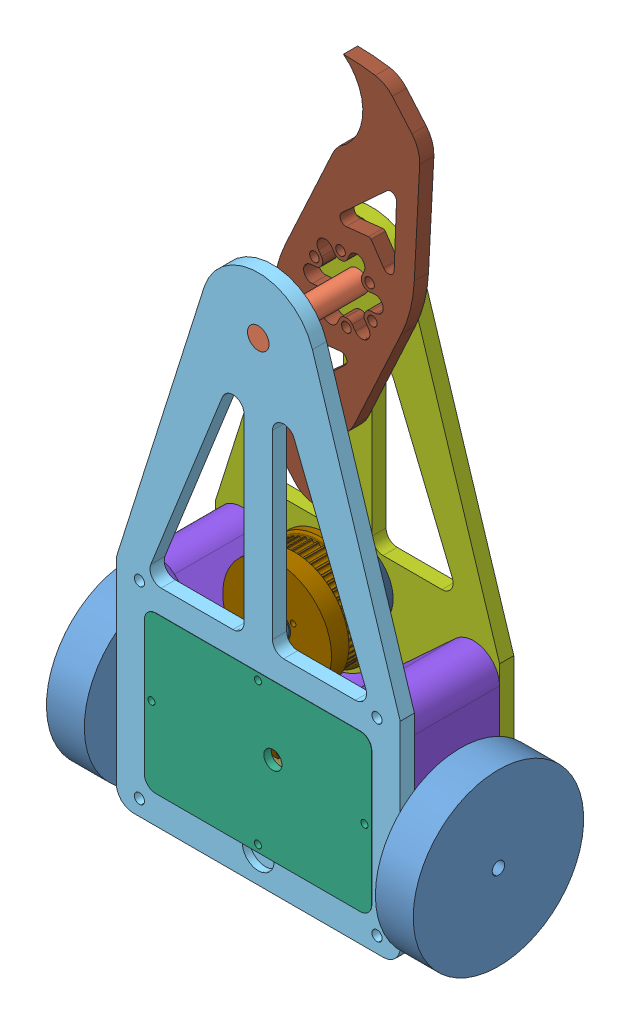
SolidWorks assembly origanal combat bot TPU, configuration Default. Lengths in mm.
Overall size (241.3 346.7 98.18).
30 component instances, 18 part files, 53 mates.
Components (placement in the parent):
- wheel-1: wheel [Default] at (-128.5875 34.925 25.4) x (-1 0 0) z (0 -0.935756 -0.352647)
- wheel-2: wheel [Default] at (1.5875 34.925 25.4) x (1 0 0) z (0 -0.978759 -0.205012)
- pin-1: pin [Default] at (-62.5126 210.1871 0) x (-0.607765 0.794117 0) z (0.794117 0.607765 0)
- 2030 4500kv with gearbox v2-1: 2030 4500kv with gearbox v2 [Default] at (-8.3063 27.0331 25.5745) x (0 -0.022102 -0.999756) z (0 -0.999756 0.022102)
- 22mm Motor Mount V1 v1-1: 22mm Motor Mount V1 v1 [Default] at (1.5875 34.925 25.4) x (0 -0.999756 0.022102) z (-1 0 0)
- 22mm Motor Mount V1 v1-2: 22mm Motor Mount V1 v1 [Default] at (-128.5875 34.925 25.4) x (0 0.999756 -0.022102) z (1 0 0)
- 2030 4500kv with gearbox v2-2: 2030 4500kv with gearbox v2 [Default] at (-118.6937 42.8169 25.2255) x (0 -0.022102 -0.999756) z (0 0.999756 -0.022102)
- Top plate-1: Top plate [Default] at (-63.5 47.625 44.45) x (0 -1 0) z (-1 0 0)
- Top cover-1: Top cover [Default] at (-63.5 47.625 47.625) x (-1 0 0) z (0 1 0)
- Bottom Plate-6: Bottom Plate [Default] at (-63.5 47.625 0) x (0 -1 0) z (-1 0 0)
- TPU Body-1: TPU Body [Default] at (-136.525 66.675 6.35) x (0 -1 0) z (-1 0 0)
- 48tooth pully_3530 motor combo-1: 48tooth pully_3530 motor combo [Default] at (-63.5 96.5708 5.35) x (0 0 1) z (0 1 0) size (36 48.63 48.63)
  - 48tooth pully_3530 motor combo.step-1: 48tooth pully_3530 motor combo.step [Default] at origin size (36 48.63 48.63)
    - 3mm 48tooth GT2 Printable v2.step-1: 3mm 48tooth GT2 Printable v2.step [Default] at (23.364 0 0) x (0 1 0) z (0 0 1) size (48.63 22.27 48.63)
    - Motor_3536.step-1: Motor_3536.step [Default] at origin size (36 35 35)
- bar weapon.STEP-1: bar weapon.STEP [Default] at (-63.5 211.8868 9.525) x (0.907959 -0.419058 0) z (0 0 1)
- 91115A203_Female Threaded Hex Standoff-1: 91115A203_Female Threaded Hex Standoff [91115A203] at (-116.6254 91.4023 25.4) x (0.5 0.866025 0) z (0 0 -1)
- 91115A203_Female Threaded Hex Standoff-2: 91115A203_Female Threaded Hex Standoff [91115A203] at (-10.3746 91.4023 25.4) x (0.5 0.866025 0) z (0 0 -1)
- 91115A203_Female Threaded Hex Standoff-3: 91115A203_Female Threaded Hex Standoff [91115A203] at (-116.6254 7.0227 25.4) x (-0.5 -0.866025 0) z (0 0 -1)
- 91115A203_Female Threaded Hex Standoff-4: 91115A203_Female Threaded Hex Standoff [91115A203] at (-10.3746 7.0227 25.4) x (-1 0 0) z (0 0 -1)
- just cuz_SwitchBoard-1: just cuz_SwitchBoard [Default] at (-56.8286 51.9533 41.05) size (48 14 17.55)
  - just cuz_SwitchBoard.stp-1: just cuz_SwitchBoard.stp [Default] at origin size (48 14 17.55)
    - XT30_Female.stp-1: XT30_Female.stp [Default] at (-4.7913 -1.9356 -6.5462) x (-1 0 0) z (0 0 -1) size (5.25 10.45 15.6)
    - XT30_Male.stp-1: XT30_Male.stp [Default] at (4.8749 -1.9112 -14.0462) size (5.25 10.45 15.5)
    - 8-32 PEM Nut Insert.stp-1: 8-32 PEM Nut Insert.stp [Default] at (0 0 -4.0856) x (1 0 0) z (0 -1 0) size (8.64 3.94 8.64)
    - XT30_Female.stp-2: XT30_Female.stp [Default] at (-10.7913 -1.9356 -6.5462) x (-1 0 0) z (0 0 -1) size (5.25 10.45 15.6)
    - XT30_Female.stp-3: XT30_Female.stp [Default] at (-16.7913 -1.9356 -6.5462) x (-1 0 0) z (0 0 -1) size (5.25 10.45 15.6)
    - 8-32 3-16 NO THREADS_ Button Head Hex Drive Screw.stp-1: 8-32 3-16 NO THREADS_ Button Head Hex Drive Screw.stp [Default] at (0 0 -0.7667) x (-1 0 0) z (0 0 1) size (7.92 7.92 6.97)
    - Switch PD Board V1.3 Bottom Connectors.stp-1: Switch PD Board V1.3 Bottom Connectors.stp [Default] at origin size (48 14 1.56)
    - Switch PD Board V1.3 Bottom Connectors-0.stp-1: Switch PD Board V1.3 Bottom Connectors-0.stp [Default] at origin size (41 14 3.4)
Mates (geometry in assembly coordinates):
- Concentric19: concentric anti-aligned: cylinder of wheel-1 through (-128.5875 34.925 25.4) axis (-1 0 0) radius 2.794; cylinder of 2030 4500kv with gearbox v2-1 through (-0.4125 34.925 25.4) axis (1 0 0) radius 3
- Parallel5: parallel anti-aligned: cylinder of wheel-2 through (1.5875 34.925 25.4) axis (1 0 0) radius 2.794; cylinder of 2030 4500kv with gearbox v2-2 through (-126.5875 34.925 25.4) axis (-1 0 0) radius 3
- Parallel14: parallel anti-aligned: plane of 2030 4500kv with gearbox v2-1 through (-0.4125 31.1877 19.4812) normal (0 -0.022102 -0.999756); plane of 22mm Motor Mount V1 v1-1 through (1.5875 31.1539 19.3684) normal (0 0.022102 0.999756)
- Concentric39: concentric anti-aligned: cylinder of 2030 4500kv with gearbox v2-1 through (-0.4125 34.925 25.4) axis (1 0 0) radius 7; cylinder of 22mm Motor Mount V1 v1-1 through (1.5875 34.925 25.4) axis (-1 0 0) radius 7.1135
- Concentric54: concentric aligned: cylinder of 22mm Motor Mount V1 v1-2 through (-128.5875 41.4281 31.6218) axis (1 0 0) radius 1.2; cylinder of 2030 4500kv with gearbox v2-2 through (-126.5875 41.4281 31.6218) axis (1 0 0) radius 1
- Concentric55: concentric aligned: cylinder of 22mm Motor Mount V1 v1-2 through (-128.5875 28.4219 19.1782) axis (1 0 0) radius 1.2; cylinder of 2030 4500kv with gearbox v2-2 through (-126.5875 28.4219 19.1782) axis (1 0 0) radius 1
- Coincident67: coincident anti-aligned: plane of Top plate-1 through (-12.7 12.7 47.625) normal (-1 0 0); plane of Top cover-1 through (-12.7 82.55 50.927) normal (1 0 0)
- Coincident68: coincident anti-aligned: plane of Top plate-1 through (-12.7 82.55 47.625) normal (0 -1 0); plane of Top cover-1 through (-12.7 82.55 50.927) normal (0 1 0)
- Coincident69: coincident anti-aligned: plane of Top plate-1 through (-63.5 47.625 47.625) normal (0 0 1); plane of Top cover-1 through (-63.5 47.625 47.625) normal (0 0 -1)
- Coincident78: coincident aligned: plane of 22mm Motor Mount V1 v1-2 through (-128.5875 34.925 25.4) normal (-1 0 0); plane of 2030 4500kv with gearbox v2-2 through (-128.5875 34.925 25.4) normal (-1 0 0)
- Concentric74: concentric anti-aligned: cylinder of pin-1 through (-63.5 211.8868 50.8) axis (0 0 -1) radius 4.826; cylinder of Top plate-1 through (-63.5 211.8868 44.45) axis (0 0 1) radius 4.826
- Coincident99: coincident anti-aligned: plane of Top plate-1 through (-63.5 47.625 44.45) normal (0 0 -1); plane of TPU Body-1 through (-136.525 66.675 44.45) normal (0 0 1)
- Coincident100: coincident aligned: plane of Bottom Plate-6 through (-127 0 6.35) normal (0 -1 0); plane of TPU Body-1 through (-127 0 44.45) normal (0 -1 0)
- Coincident101: coincident aligned: plane of Top plate-1 through (-127 95.25 50.8) normal (-1 0 0); plane of TPU Body-1 through (-127 95.25 44.45) normal (-1 0 0)
- Coincident102: coincident anti-aligned: plane of Bottom Plate-6 through (-63.5 47.625 6.35) normal (0 0 1); plane of TPU Body-1 through (-136.525 66.675 6.35) normal (0 0 -1)
- Coincident103: coincident aligned: plane of Top plate-1 through (-127 0 50.8) normal (0 -1 0); plane of TPU Body-1 through (-127 0 44.45) normal (0 -1 0)
- Coincident104: coincident aligned: plane of Bottom Plate-6 through (-127 95.25 6.35) normal (-1 0 0); plane of TPU Body-1 through (-127 95.25 44.45) normal (-1 0 0)
- Coincident105: coincident aligned: plane of pin-1 through (-63.5 211.8868 50.8) normal (0 0 1); plane of Top plate-1 through (-63.5 47.625 50.8) normal (0 0 1)
- Coincident106: coincident anti-aligned: plane of TPU Body-1 through (-127 0 44.45) normal (0 -1 0)
- Concentric75: concentric anti-aligned: cylinder of wheel-2 through (1.5875 34.925 25.4) axis (1 0 0) radius 2.794; cylinder of 2030 4500kv with gearbox v2-2 through (-126.5875 34.925 25.4) axis (-1 0 0) radius 3
- Coincident125: coincident anti-aligned: plane of Bottom Plate-6 through (-63.5 47.625 0) normal (0 0 -1)
- Coincident126: coincident aligned: plane of TPU Body-1 through (0 6.35 -120.8087) normal (1 0 0)
- Coincident127: coincident anti-aligned: plane of TPU Body-1 through (-127 0 44.45) normal (0 -1 0)
- Coincident129: coincident anti-aligned: plane of 22mm Motor Mount V1 v1-1 through (0 34.925 25.4) normal (-1 0 0); plane of TPU Body-1 through (0 6.35 -120.8087) normal (1 0 0)
- Coincident132: coincident anti-aligned: plane of 22mm Motor Mount V1 v1-2 through (-127 34.925 25.4) normal (1 0 0); plane of TPU Body-1 through (-127 95.25 44.45) normal (-1 0 0)
- Coincident133: coincident aligned: plane of 2030 4500kv with gearbox v2-1 through (1.5875 34.925 25.4) normal (1 0 0); plane of 22mm Motor Mount V1 v1-1 through (1.5875 34.925 25.4) normal (1 0 0)
- Coincident137: coincident anti-aligned: plane of wheel-2 through (1.5875 34.925 25.4) normal (-1 0 0); plane of 22mm Motor Mount V1 v1-1 through (1.5875 34.925 25.4) normal (1 0 0)
- Coincident138: coincident anti-aligned: plane of wheel-1 through (-128.5875 34.925 25.4) normal (1 0 0); plane of 22mm Motor Mount V1 v1-2 through (-128.5875 34.925 25.4) normal (-1 0 0)
- Coincident140: coincident anti-aligned: plane of Bottom Plate-6 through (-63.5 47.625 6.35) normal (0 0 1); plane of 48tooth pully_3530 motor combo-1/48tooth pully_3530 motor combo.step-1/Motor_3536.step-1 through (-63.5 80.6958 6.35) normal (0 0 -1)
- Concentric94: concentric anti-aligned: circle of Bottom Plate-6; circle of 48tooth pully_3530 motor combo-1/48tooth pully_3530 motor combo.step-1/Motor_3536.step-1
- Concentric98: concentric anti-aligned: cylinder of 2030 4500kv with gearbox v2-1 through (-0.4125 34.925 25.4) axis (-1 0 0) radius 11; cylinder of TPU Body-1 through (-127 34.925 25.4) axis (1 0 0) radius 11
- Concentric99: concentric anti-aligned: cylinder of 22mm Motor Mount V1 v1-1 through (1.5875 22.0527 17.7451) axis (-1 0 0) radius 2.1526; cylinder of TPU Body-1 through (-127 22.0527 17.7451) axis (1 0 0) radius 2.1526
- Concentric100: concentric aligned: cylinder of 2030 4500kv with gearbox v2-2 through (-126.5875 34.925 25.4) axis (1 0 0) radius 11; cylinder of TPU Body-1 through (-127 34.925 25.4) axis (1 0 0) radius 11
- Concentric101: concentric aligned: cylinder of 22mm Motor Mount V1 v1-2 through (-128.5875 22.0527 17.7451) axis (1 0 0) radius 2.1526; cylinder of TPU Body-1 through (-127 22.0527 17.7451) axis (1 0 0) radius 2.1526
- Parallel15: parallel anti-aligned: plane of 48tooth pully_3530 motor combo-1/48tooth pully_3530 motor combo.step-1/Motor_3536.step-1 through (-63.5 96.5708 5.35) normal (0 -1 0)
- Coincident141: coincident anti-aligned: plane of Bottom Plate-6 through (-63.5 47.625 6.35) normal (0 0 1); plane of bar weapon.STEP-1 through (-95.5656 234.1278 6.35) normal (0 0 -1)
- Coincident142: coincident anti-aligned: cylinder of pin-1 through (-63.5 211.8868 50.8) axis (0 0 -1) radius 4.826; circle of bar weapon.STEP-1
- Coincident143: coincident anti-aligned: plane of Bottom Plate-6 through (-63.5 47.625 6.35) normal (0 0 1); plane of 91115A203_Female Threaded Hex Standoff-1 through (-116.6254 91.4023 6.35) normal (0 0 -1)
- Coincident156: coincident anti-aligned: plane of Bottom Plate-6 through (-63.5 47.625 6.35) normal (0 0 1); plane of 91115A203_Female Threaded Hex Standoff-3 through (-116.6254 7.0227 6.35) normal (0 0 -1)
- Coincident157: coincident anti-aligned: plane of TPU Body-1 through (-93.0205 41.5576 -12.9998) normal (-0.866025 0.5 0); plane of 91115A203_Female Threaded Hex Standoff-3 through (-112.9592 7.0227 44.45) normal (0.866025 -0.5 0)
- Coincident158: coincident anti-aligned: plane of TPU Body-1 through (-114.7923 3.8477 6.35) normal (0 1 0); plane of 91115A203_Female Threaded Hex Standoff-3 through (-114.7923 3.8477 44.45) normal (0 -1 0)
- Coincident159: coincident anti-aligned: plane of Bottom Plate-6 through (-63.5 47.625 6.35) normal (0 0 1); plane of 91115A203_Female Threaded Hex Standoff-4 through (-10.3746 7.0227 6.35) normal (0 0 -1)
- Coincident160: coincident anti-aligned: plane of TPU Body-1 through (-8.5415 3.8477 6.35) normal (-0.866025 0.5 0); plane of 91115A203_Female Threaded Hex Standoff-4 through (-6.7084 7.0227 44.45) normal (0.866025 -0.5 0)
- Coincident161: coincident anti-aligned: plane of TPU Body-1 through (-64.9928 107.9742 -12.9998) normal (-0.866025 -0.5 0); plane of 91115A203_Female Threaded Hex Standoff-4 through (-8.5415 10.1977 44.45) normal (0.866025 0.5 0)
- Coincident162: coincident anti-aligned: plane of Bottom Plate-6 through (-63.5 47.625 6.35) normal (0 0 1); plane of 91115A203_Female Threaded Hex Standoff-2 through (-10.3746 91.4023 6.35) normal (0 0 -1)
- Concentric104: concentric aligned: cylinder of Bottom Plate-6 through (-42.3285 53.9533 0) axis (0 0 1) radius 1.83; cylinder of just cuz_SwitchBoard-1/just cuz_SwitchBoard.stp-1/Switch PD Board V1.3 Bottom Connectors.stp-1 through (-42.3285 53.9533 39.514) axis (0 0 1) radius 1.83
- Concentric105: concentric aligned: cylinder of Bottom Plate-6 through (-83.3289 53.9535 0) axis (0 0 1) radius 1.83; cylinder of just cuz_SwitchBoard-1/just cuz_SwitchBoard.stp-1/Switch PD Board V1.3 Bottom Connectors.stp-1 through (-83.3289 53.9535 39.514) axis (0 0 1) radius 1.83
- Coincident166: coincident anti-aligned: plane of Top plate-1 through (-63.5 47.625 44.45) normal (0 0 -1); plane of just cuz_SwitchBoard-1/just cuz_SwitchBoard.stp-1/Switch PD Board V1.3 Bottom Connectors-0.stp-1 through (-62.8286 53.9534 44.45) normal (0 0 1)
- Coincident167: coincident anti-aligned: plane of TPU Body-1 through (-136.525 88.2273 -12.9998) normal (0 1 0); plane of 91115A203_Female Threaded Hex Standoff-2 through (-8.5415 88.2273 44.45) normal (0 -1 0)
- Coincident168: coincident anti-aligned: plane of TPU Body-1 through (-49.8698 16.6446 -12.9998) normal (-0.866025 0.5 0); plane of 91115A203_Female Threaded Hex Standoff-2 through (-6.7084 91.4023 44.45) normal (0.866025 -0.5 0)
- Coincident169: coincident anti-aligned: plane of TPU Body-1 through (-108.1434 83.0611 -12.9998) normal (-0.866025 -0.5 0); plane of 91115A203_Female Threaded Hex Standoff-1 through (-114.7923 94.5773 44.45) normal (0.866025 0.5 0)
- Coincident170: coincident anti-aligned: plane of TPU Body-1 through (-129.5579 62.6525 -12.9998) normal (-0.866025 0.5 0); plane of 91115A203_Female Threaded Hex Standoff-1 through (-112.9592 91.4023 44.45) normal (0.866025 -0.5 0)
- Parallel16: parallel: plane of Top plate-1 through (-57.15 205.5368 44.45) normal (1 0 0); line of bar weapon.STEP-1 through (-63.5 211.8868 12.7) axis (0 1 0)
